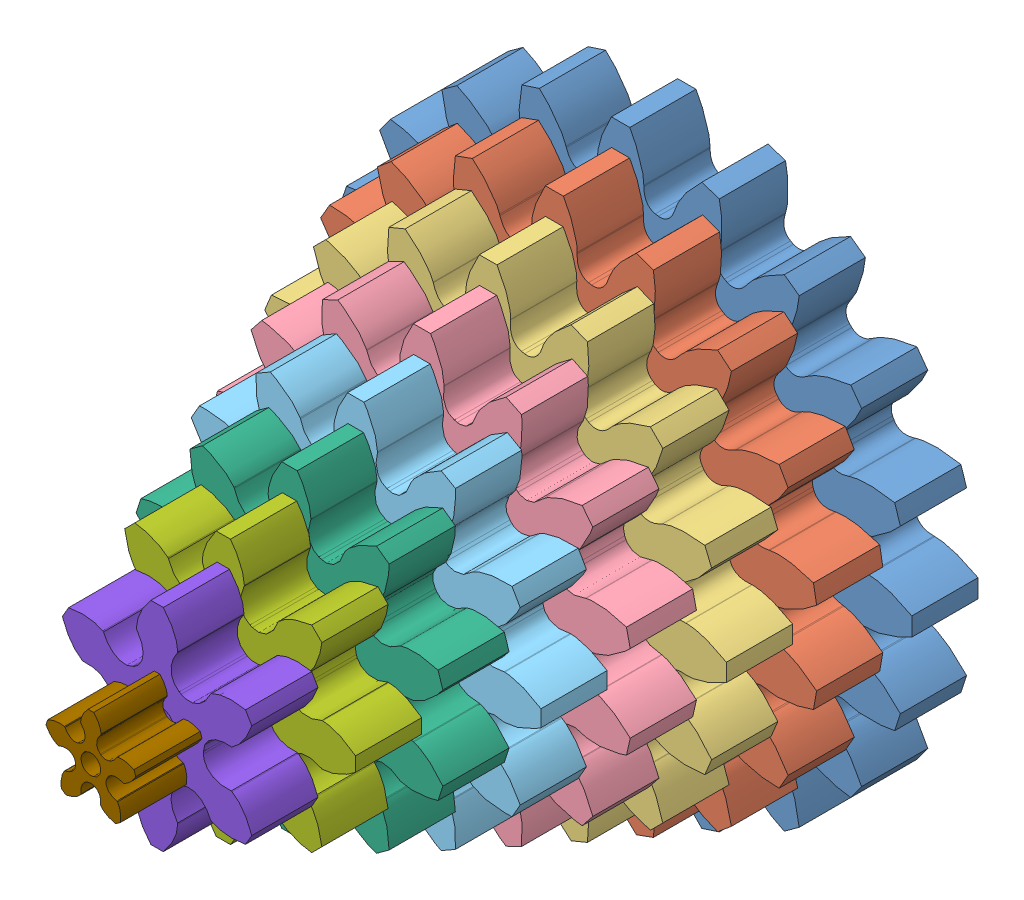
SolidWorks assembly one_tree, configuration Default. Lengths in mm.
Overall size (88 88 90).
9 component instances, 9 part files, 0 mates.
Components (placement in the parent):
- tree2a-1: tree2a [Gear Blank] at origin size (88 88 10)
- tree2b-2: tree2b [Gear Blank] at (0 0 10) size (79.21 80 10)
- tree2c-1: tree2c [Gear Blank] at (0 0 20) size (72 72 10)
- tree2d-1: tree2d [Gear Blank] at (0 0 30) size (62.92 64 10)
- tree2e-1: tree2e [Gear Blank] at (0 0 40) size (56 56 10)
- tree2f-1: tree2f [Gear Blank] at (0 0 50) size (46.32 48 10)
- tree2g-1: tree2g [Gear Blank] at (0 0 60) size (40 40 10)
- tree2h-1: tree2h [Gear Blank] at (0 0 70) size (28.6 32 10)
- tree2star-1: tree2star [Gear Blank] at (0 0 80) size (13.55 12.9 10)
